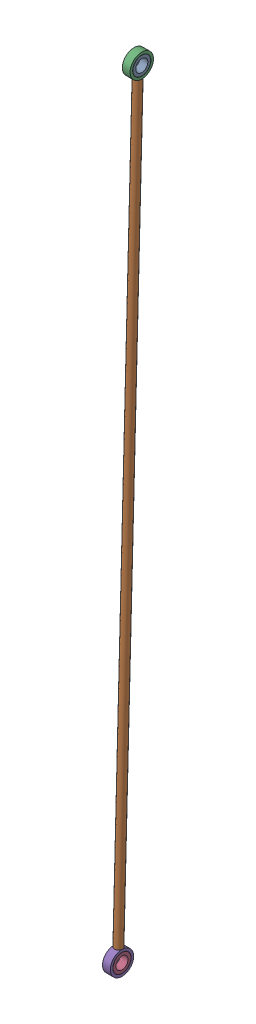
SolidWorks assembly steering_control_rod, configuration Default. Lengths in mm.
Overall size (7.04 515.84 28.53).
5 component instances, 3 part files, 9 mates.
Components (placement in the parent):
- Bearing-1: Bearing [Default] at (4.1181 5.8339 10.616) size (5.08 12.7 12.7)
- Linkage_2nd-1: Linkage_2nd [Default] at (4.1181 -486.7623 23.3198) x (-0.832657 -0.014277 -0.553605) z (0 0.999668 -0.025781) size (5.08 5.08 485.14)
- Ring-1: Ring [Default] at (4.1181 5.8339 10.616) x (1 0 0) z (0 0.025781 0.999668) size (5.08 40.64 15.24)
- Bearing-2: Bearing [Default] at (4.1181 -494.3798 23.5163) x (1 0 0) z (0 -0.018873 0.999822) size (5.08 12.7 12.7)
- Ring-2: Ring [Default] at (4.1181 -494.3798 23.5163) x (-1 0 0) z (0 0.025781 0.999668) size (5.08 40.64 15.24)
Mates (geometry in assembly coordinates):
- Concentric1: concentric: sphere of Bearing-1; sphere of Ring-1
- Concentric2: concentric aligned: cylinder of Linkage_2nd-1 through (4.1181 -1.7836 10.8125) axis (0 -0.999668 0.025781) radius 1.27; cylinder of Ring-1 through (4.1181 -27.1751 11.4673) axis (0 -0.999668 0.025781) radius 1.27
- Tangent1: tangent anti-aligned: plane of Linkage_2nd-1 through (4.1181 -1.7836 10.8125) normal (0 0.999668 -0.025781); cylinder of Ring-1 through (-6.0419 5.8339 10.616) axis (-1 0 0) radius 7.62
- Concentric3: concentric: sphere of Bearing-2; sphere of Ring-2
- Concentric4: concentric anti-aligned: cylinder of Linkage_2nd-1 through (4.1181 -1.7836 10.8125) axis (0 -0.999668 0.025781) radius 1.27; cylinder of Ring-2 through (4.1181 -461.3708 22.665) axis (0 0.999668 -0.025781) radius 1.27
- Tangent2: tangent anti-aligned: plane of Linkage_2nd-1 through (4.1181 -486.7623 23.3198) normal (0 -0.999668 0.025781); cylinder of Ring-2 through (14.2781 -494.3798 23.5163) axis (1 0 0) radius 7.62
- Concentric6: concentric aligned: circle of Bearing-2; circle of Ring-2
- Coincident1: coincident anti-aligned: circle of Bearing-1; plane of Ring-1 through (1.5781 5.8339 10.616) normal (-1 0 0)
- Coincident2: coincident aligned: plane of Ring-1 through (1.5781 5.8339 10.616) normal (-1 0 0); plane of Ring-2 through (1.5781 -494.3798 23.5163) normal (-1 0 0)
